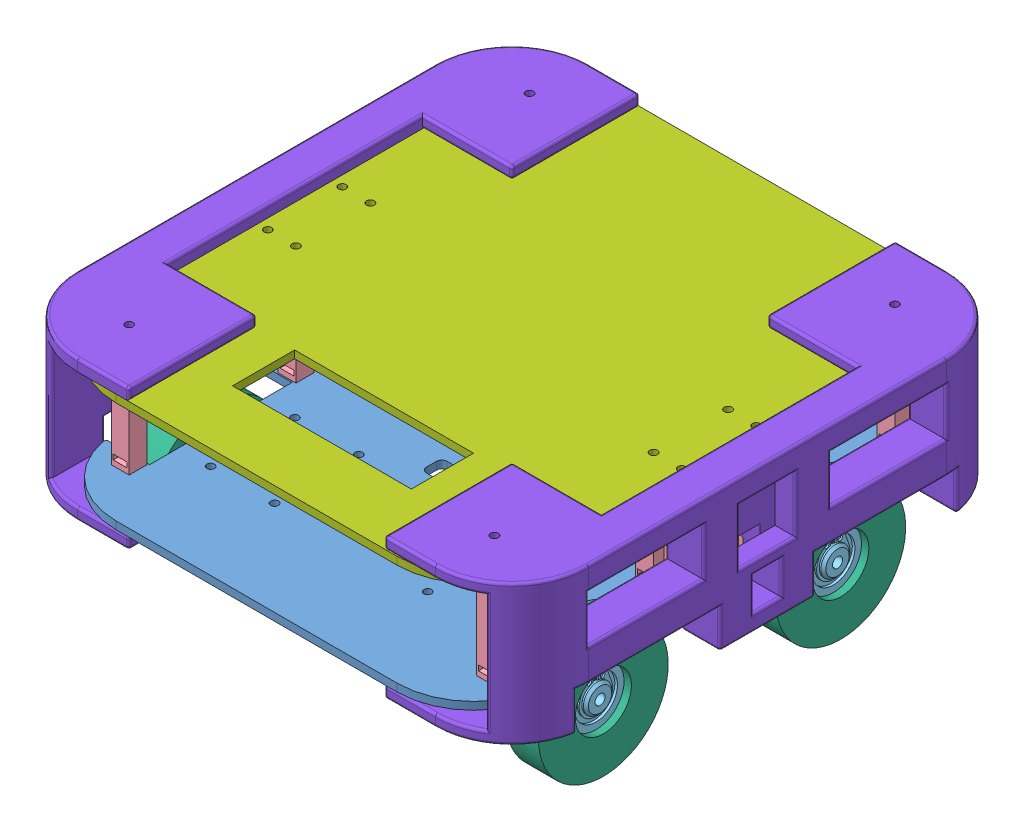
SolidWorks assembly MazeRobot, configuration Default. Lengths in mm.
Overall size (200 92.27 200).
32 component instances, 8 part files, 48 mates.
Components (placement in the parent):
- MazeBase-1: MazeBase [Default] at (81.1671 97.1233 140.7945) size (170 3 200)
- pololuMotorHolder-1: pololuMotorHolder [Default] at (13.6583 80.758 94.3145) x (0 0 -1) z (1 0 0) size (38 30.37 50.03)
- pololuMotorHolder-2: pololuMotorHolder [Default] at (13.6583 80.758 187.2745) x (0 0 -1) z (1 0 0) size (38 30.37 50.03)
- pololuMotorHolder-3: pololuMotorHolder [Default] at (148.6758 80.758 187.2745) x (0 0 1) z (-1 0 0) size (38 30.37 50.03)
- pololuMotorHolder-4: pololuMotorHolder [Default] at (148.6758 80.758 94.3145) x (0 0 1) z (-1 0 0) size (38 30.37 50.03)
- Pololu 25D gear motor with encoder part no 2275-1: Pololu 25D gear motor with encoder part no 2275 [Default] at (141.6758 80.758 94.3145) x (0 0.983333 0.181815) z (1 0 0) size (25 25 75.81)
- Pololu 25D gear motor with encoder part no 2275-2: Pololu 25D gear motor with encoder part no 2275 [Default] at (20.6583 80.758 94.3145) x (0 -0.940392 -0.340091) z (-1 0 0) size (25 25 75.81)
- Pololu 25D gear motor with encoder part no 2275-3: Pololu 25D gear motor with encoder part no 2275 [Default] at (141.6758 80.758 187.2745) x (0 -1 0) z (1 0 0) size (25 25 75.81)
- Pololu 25D gear motor with encoder part no 2275-4: Pololu 25D gear motor with encoder part no 2275 [Default] at (20.6583 80.758 187.2745) x (0 0.71834 -0.695692) z (-1 0 0) size (25 25 75.81)
- poste-1: poste [Default] at (9.6671 100.1233 62.4145) size (7 40 7)
- poste-4: poste [Default] at (0.1671 100.1233 126.2145) x (0 0 -1) z (1 0 0) size (7 40 7)
- poste-5: poste [Default] at (11.1671 100.1233 155.3745) size (7 40 7)
- poste-6: poste [Default] at (0.1671 100.1233 155.3745) x (0 0 -1) z (1 0 0) size (7 40 7)
- poste-7: poste [Default] at (11.1671 100.1233 126.2145) size (7 40 7)
- poste-8: poste [Default] at (9.6671 100.1233 219.1745) size (7 40 7)
- poste-9: poste [Default] at (152.6671 100.1233 219.1745) size (7 40 7)
- poste-10: poste [Default] at (152.6671 100.1233 62.4145) size (7 40 7)
- poste-11: poste [Default] at (151.1671 100.1233 155.3745) size (7 40 7)
- poste-12: poste [Default] at (151.1671 100.1233 126.2145) size (7 40 7)
- poste-13: poste [Default] at (162.1671 100.1233 126.2145) x (0 0 -1) z (1 0 0) size (7 40 7)
- poste-14: poste [Default] at (162.1671 100.1233 155.3745) x (0 0 -1) z (1 0 0) size (7 40 7)
- Snap_Hub_4mmx050-2: Snap_Hub_4mmx050 [Default] at (149.1758 80.758 187.2745) x (0 0 -1) z (1 0 0) size (22 22 12.95)
- Snap_Hub_4mmx050-3: Snap_Hub_4mmx050 [Default] at (149.1758 80.758 94.3145) x (0 0 -1) z (1 0 0) size (22 22 12.95)
- Snap_Hub_4mmx050-4: Snap_Hub_4mmx050 [Default] at (13.1583 80.758 94.3145) x (0 0 1) z (-1 0 0) size (22 22 12.95)
- Snap_Hub_4mmx050-5: Snap_Hub_4mmx050 [Default] at (13.1583 80.758 187.2745) x (0 0 1) z (-1 0 0) size (22 22 12.95)
- wheel-2: wheel [Default] at (-1.0657 80.758 187.2745) x (0 1 0) z (0 0 -1) size (50.8 12.7 50.8)
- wheel-4: wheel [Default] at (-1.0657 80.758 94.3145) x (0 0 -1) z (0 -1 0) size (50.8 12.7 50.8)
- wheel-5: wheel [Default] at (150.6998 80.758 94.3145) x (0 1 0) z (0 0 -1) size (50.8 12.7 50.8)
- wheel-6: wheel [Default] at (150.6998 80.758 187.2745) x (0 0 -1) z (0 -1 0) size (50.8 12.7 50.8)
- MazeTop-3: MazeTop [Default] at (81.1671 140.1233 140.7945) x (0 0 -1) z (1 0 0) size (200 3 170)
- LateralBumper-1: LateralBumper [Default] at (131.1671 120.1233 140.7945) x (0 0 -1) z (1 0 0) size (200 55 50)
- LateralBumper-2: LateralBumper [Default] at (31.1671 120.1233 140.7945) x (0 0 1) z (-1 0 0) size (200 55 50)
Mates (geometry in assembly coordinates):
- Coincident1: coincident aligned: circle of MazeBase-1; circle of pololuMotorHolder-1
- Coincident2: coincident aligned: circle of MazeBase-1; circle of pololuMotorHolder-2
- Coincident3: coincident aligned: plane of MazeBase-1 through (81.1671 97.1233 140.7945) normal (0 -1 0); circle of pololuMotorHolder-3
- Coincident4: coincident aligned: circle of MazeBase-1; circle of pololuMotorHolder-4
- Coincident5: coincident aligned: circle of MazeBase-1; circle of pololuMotorHolder-3
- Coincident6: coincident anti-aligned: plane of pololuMotorHolder-4 through (146.6758 80.758 94.3145) normal (-1 0 0); plane of Pololu 25D gear motor with encoder part no 2275-1 through (146.6758 80.758 94.3145) normal (1 0 0)
- Concentric1: concentric aligned: cylinder of pololuMotorHolder-4 through (146.6758 80.758 94.3145) axis (-1 0 0) radius 12.7918; cylinder of Pololu 25D gear motor with encoder part no 2275-1 through (146.6758 80.758 94.3145) axis (-1 0 0) radius 12.5
- Coincident7: coincident anti-aligned: plane of pololuMotorHolder-1 through (15.6583 80.758 94.3145) normal (1 0 0); plane of Pololu 25D gear motor with encoder part no 2275-2 through (15.6583 80.758 94.3145) normal (-1 0 0)
- Concentric2: concentric aligned: cylinder of pololuMotorHolder-1 through (15.6583 80.758 94.3145) axis (1 0 0) radius 12.7918; cylinder of Pololu 25D gear motor with encoder part no 2275-2 through (15.6583 80.758 94.3145) axis (1 0 0) radius 12.5
- Coincident9: coincident anti-aligned: plane of pololuMotorHolder-3 through (146.6758 80.758 187.2745) normal (-1 0 0); plane of Pololu 25D gear motor with encoder part no 2275-3 through (146.6758 80.758 187.2745) normal (1 0 0)
- Concentric3: concentric aligned: cylinder of pololuMotorHolder-3 through (146.6758 80.758 187.2745) axis (-1 0 0) radius 12.7918; cylinder of Pololu 25D gear motor with encoder part no 2275-3 through (146.6758 80.758 187.2745) axis (-1 0 0) radius 12.5
- Coincident10: coincident anti-aligned: plane of pololuMotorHolder-2 through (15.6583 80.758 187.2745) normal (1 0 0); plane of Pololu 25D gear motor with encoder part no 2275-4 through (15.6583 80.758 187.2745) normal (-1 0 0)
- Concentric4: concentric aligned: cylinder of pololuMotorHolder-2 through (15.6583 80.758 187.2745) axis (1 0 0) radius 12.7918; cylinder of Pololu 25D gear motor with encoder part no 2275-4 through (15.6583 80.758 187.2745) axis (1 0 0) radius 12.5
- Coincident11: coincident: circle of MazeBase-1; circle of poste-1
- Coincident13: coincident: circle of MazeBase-1; circle of poste-4
- Coincident14: coincident: circle of MazeBase-1; circle of poste-5
- Coincident15: coincident: circle of MazeBase-1; circle of poste-6
- Coincident16: coincident: circle of MazeBase-1; circle of poste-7
- Coincident17: coincident: circle of MazeBase-1; circle of poste-8
- Coincident18: coincident: circle of MazeBase-1; circle of poste-9
- Coincident19: coincident: circle of MazeBase-1; circle of poste-11
- Coincident20: coincident: circle of MazeBase-1; circle of poste-12
- Coincident21: coincident: circle of MazeBase-1; circle of poste-10
- Coincident22: coincident: circle of MazeBase-1; circle of poste-13
- Coincident23: coincident: circle of MazeBase-1; circle of poste-14
- Concentric5: concentric: cylinder of Pololu 25D gear motor with encoder part no 2275-3 through (159.1758 80.758 187.2745) axis (-1 0 0) radius 2; cylinder of Snap_Hub_4mmx050-2 through (162.1298 80.758 187.2745) axis (-1 0 0) radius 2
- Coincident24: coincident: circle of MazeBase-1; circle of pololuMotorHolder-3
- Coincident25: coincident: plane of Pololu 25D gear motor with encoder part no 2275-3 through (149.1758 80.758 187.2745) normal (1 0 0); plane of Snap_Hub_4mmx050-2 through (149.1758 77.622 184.1385) normal (-1 0 0)
- Concentric6: concentric: cylinder of Pololu 25D gear motor with encoder part no 2275-1 through (159.1758 80.758 94.3145) axis (-1 0 0) radius 2; cylinder of Snap_Hub_4mmx050-3 through (162.1298 80.758 94.3145) axis (-1 0 0) radius 2
- Coincident26: coincident: plane of Pololu 25D gear motor with encoder part no 2275-1 through (149.1758 80.758 94.3145) normal (1 0 0); plane of Snap_Hub_4mmx050-3 through (149.1758 77.622 91.1785) normal (-1 0 0)
- Concentric7: concentric: cylinder of Pololu 25D gear motor with encoder part no 2275-2 through (3.1583 80.758 94.3145) axis (1 0 0) radius 2; cylinder of Snap_Hub_4mmx050-4 through (0.2043 80.758 94.3145) axis (1 0 0) radius 2
- Coincident27: coincident: plane of Pololu 25D gear motor with encoder part no 2275-2 through (13.1583 80.758 94.3145) normal (-1 0 0); plane of Snap_Hub_4mmx050-4 through (13.1583 77.622 97.4504) normal (1 0 0)
- Concentric8: concentric: cylinder of Pololu 25D gear motor with encoder part no 2275-4 through (3.1583 80.758 187.2745) axis (1 0 0) radius 2; cylinder of Snap_Hub_4mmx050-5 through (0.2043 80.758 187.2745) axis (1 0 0) radius 2
- Coincident28: coincident: plane of Pololu 25D gear motor with encoder part no 2275-4 through (13.1583 80.758 187.2745) normal (-1 0 0); plane of Snap_Hub_4mmx050-5 through (13.1583 77.622 190.4104) normal (1 0 0)
- Concentric12: concentric: cylinder of Snap_Hub_4mmx050-5 through (3.8365 80.758 187.2745) axis (-1 0 0) radius 10.9985; cylinder of wheel-2 through (-48.3657 80.758 187.2745) axis (1 0 0) radius 11
- Concentric13: concentric: circle of Snap_Hub_4mmx050-5; circle of wheel-2
- Concentric14: concentric: circle of Snap_Hub_4mmx050-5; circle of wheel-2
- Coincident29: coincident: circle of Snap_Hub_4mmx050-5; plane of wheel-2 through (11.6343 80.758 187.2745) normal (1 0 0)
- Concentric15: concentric: cylinder of Snap_Hub_4mmx050-4 through (9.9579 80.758 94.3145) axis (1 0 0) radius 10.9985; cylinder of wheel-4 through (-48.3657 80.758 94.3145) axis (1 0 0) radius 11
- Coincident30: coincident: circle of Snap_Hub_4mmx050-4; plane of wheel-4 through (11.6343 80.758 94.3145) normal (1 0 0)
- Concentric16: concentric: cylinder of Snap_Hub_4mmx050-3 through (152.3762 80.758 94.3145) axis (-1 0 0) radius 10.9985; cylinder of wheel-5 through (103.3998 80.758 94.3145) axis (1 0 0) radius 11
- Concentric17: concentric: circle of Snap_Hub_4mmx050-3; circle of wheel-5
- Coincident31: coincident: circle of Snap_Hub_4mmx050-3; plane of wheel-5 through (150.6998 80.758 94.3145) normal (-1 0 0)
- Concentric18: concentric: cylinder of Snap_Hub_4mmx050-2 through (152.3762 80.758 187.2745) axis (-1 0 0) radius 10.9985; cylinder of wheel-6 through (103.3998 80.758 187.2745) axis (1 0 0) radius 11
- Coincident32: coincident: circle of Snap_Hub_4mmx050-2; plane of wheel-6 through (150.6998 80.758 187.2745) normal (-1 0 0)
- Coincident33: coincident aligned: circle of poste-8; circle of MazeTop-3
- Coincident34: coincident aligned: circle of MazeTop-3; circle of LateralBumper-1
- Coincident35: coincident aligned: circle of MazeTop-3; circle of LateralBumper-2
